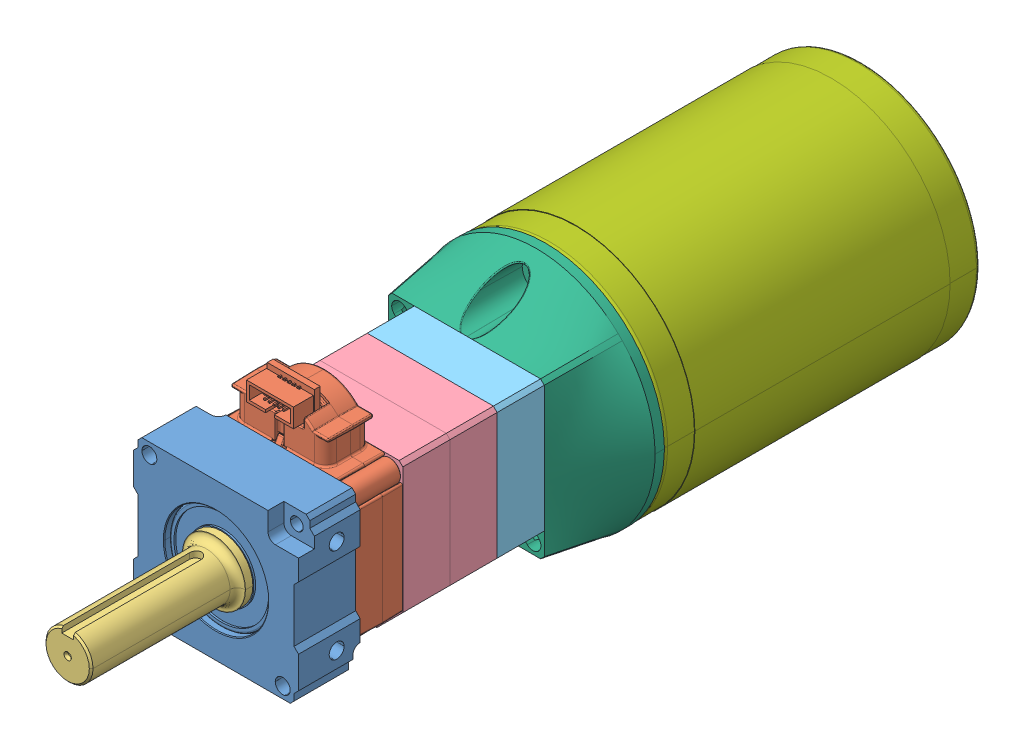
SolidWorks assembly 12220106-051 MiniCIM Motor Assembly, configuration Default. Lengths in mm.
Overall size (64.01 67.32 218.97).
11 component instances, 8 part files, 10 mates.
Components (placement in the parent):
- Gearbox Assembly-1: Gearbox Assembly [Default] at (34.0244 -12.4567 -92.7758) x (0 0 1) z (-1 0 0) size (123.35 56.32 44.45)
  - Output Housing-2: Output Housing [Default] at (64.8023 -0.856 18.2213) x (1 0 0) z (0 -1 0) size (75.7 44.45 56.32)
    - Housing-1: Housing [Default] at (19.8785 -6.4219 -11.5232) size (18.13 44.45 42)
    - Encoder.step-1: Encoder.step [Default] at (12.6785 15.8031 -11.5232) x (0 0 1) z (-1 0 0) size (56.32 42 21.21)
    - Gearbox_output_shaft-1: Gearbox_output_shaft [Default] at origin size (63.51 17 17)
  - Ring Gears-1: Ring Gears [Default] at (71.9808 10.6671 11.7994) x (1 0 0) z (0 -1 0) size (32.2 42 42)
  - Ring Gear Stage 3-1: Ring Gear Stage 3 [Default] at (59.2808 10.6671 11.7994) x (1 0 0) z (0 -1 0) size (28.65 42 42)
- CIM Adaptor.step-1: CIM Adaptor.step [Default] at (0 -1.7896 -68.72) x (0 -1 0) z (-1 0 0) size (64.01 21.63 64.01)
- Mini CIM-1: Mini CIM [Default] at (0 -1.7896 -80.245) x (0 0 -1) z (1 0 0) size (101.22 64.01 64.01)
- 8-32 X 3IN LG - Black-Oxide Alloy Steel Socket Head Screw (90044A516)-1: 8-32 X 3IN LG - Black-Oxide Alloy Steel Socket Head Screw (90044A516) [90044A516] at (17.5 15.7104 -75.245) x (-0.08536 0.99635 0) z (0 0 -1) size (6.86 6.86 81.33)
- 8-32 X 3IN LG - Black-Oxide Alloy Steel Socket Head Screw (90044A516)-3: 8-32 X 3IN LG - Black-Oxide Alloy Steel Socket Head Screw (90044A516) [90044A516] at (-17.5 -19.2896 -75.245) x (-0.242255 0.970213 0) z (0 0 -1) size (6.86 6.86 81.33)
Mates (geometry in assembly coordinates):
- Concentric3: concentric aligned: cylinder of CIM Adaptor.step-1 through (0 23.6104 -80.245) axis (0 0 1) radius 2.5527; cylinder of Mini CIM-1 through (0 23.6104 -80.245) axis (0 0 1) radius 2.0193
- Coincident3: coincident anti-aligned: plane of CIM Adaptor.step-1 through (0 -1.7896 -80.245) normal (0 0 -1); plane of Mini CIM-1 through (0 7.7354 -80.245) normal (0 0 1)
- Concentric4: concentric aligned: cylinder of CIM Adaptor.step-1 through (0 -27.1896 -80.245) axis (0 0 1) radius 2.5527; cylinder of Mini CIM-1 through (0 -27.1896 -80.245) axis (0 0 1) radius 2.0193
- Concentric5: concentric aligned: cylinder of Gearbox Assembly-1/Ring Gear Stage 3-1 through (0 -1.7896 -66.241) axis (0 0 -1) radius 4.005; cylinder of Mini CIM-1 through (0 -1.7896 -80.245) axis (0 0 -1) radius 4
- Coincident6: coordinate: point of Gearbox Assembly-1/Output Housing-2/Keyed Output Shaft.step-1
- Coincident7: coincident aligned: line of Gearbox Assembly-1/Ring Gear Stage 3-1 through (-21 12.2104 -58.895) axis (0 -1 0); line of CIM Adaptor.step-1 through (-21 18.2104 -58.895) axis (0 -1 0)
- Concentric6: concentric anti-aligned: cylinder of Gearbox Assembly-1/Ring Gear Stage 3-1 through (17.5 15.7104 -46.195) axis (0 0 1) radius 2.1526; cylinder of 8-32 X 3IN LG - Black-Oxide Alloy Steel Socket Head Screw (90044A516)-1 through (17.5 15.7104 -77.4548) axis (0 0 -1) radius 3.429
- Coincident8: coincident anti-aligned: plane of CIM Adaptor.step-1 through (17.9605 16.1709 -75.245) normal (0 0 -1); plane of 8-32 X 3IN LG - Black-Oxide Alloy Steel Socket Head Screw (90044A516)-1 through (14.4252 15.447 -75.245) normal (0 0 1)
- Concentric8: concentric anti-aligned: cylinder of Gearbox Assembly-1/Ring Gear Stage 3-1 through (-17.5 -19.2896 -46.195) axis (0 0 1) radius 2.1526; cylinder of 8-32 X 3IN LG - Black-Oxide Alloy Steel Socket Head Screw (90044A516)-3 through (-17.5 -19.2896 -77.4548) axis (0 0 -1) radius 3.429
- Coincident9: coincident anti-aligned: plane of CIM Adaptor.step-1 through (-17.9605 -19.7501 -75.245) normal (0 0 -1); plane of 8-32 X 3IN LG - Black-Oxide Alloy Steel Socket Head Screw (90044A516)-3 through (-20.4942 -20.0372 -75.245) normal (0 0 1)
